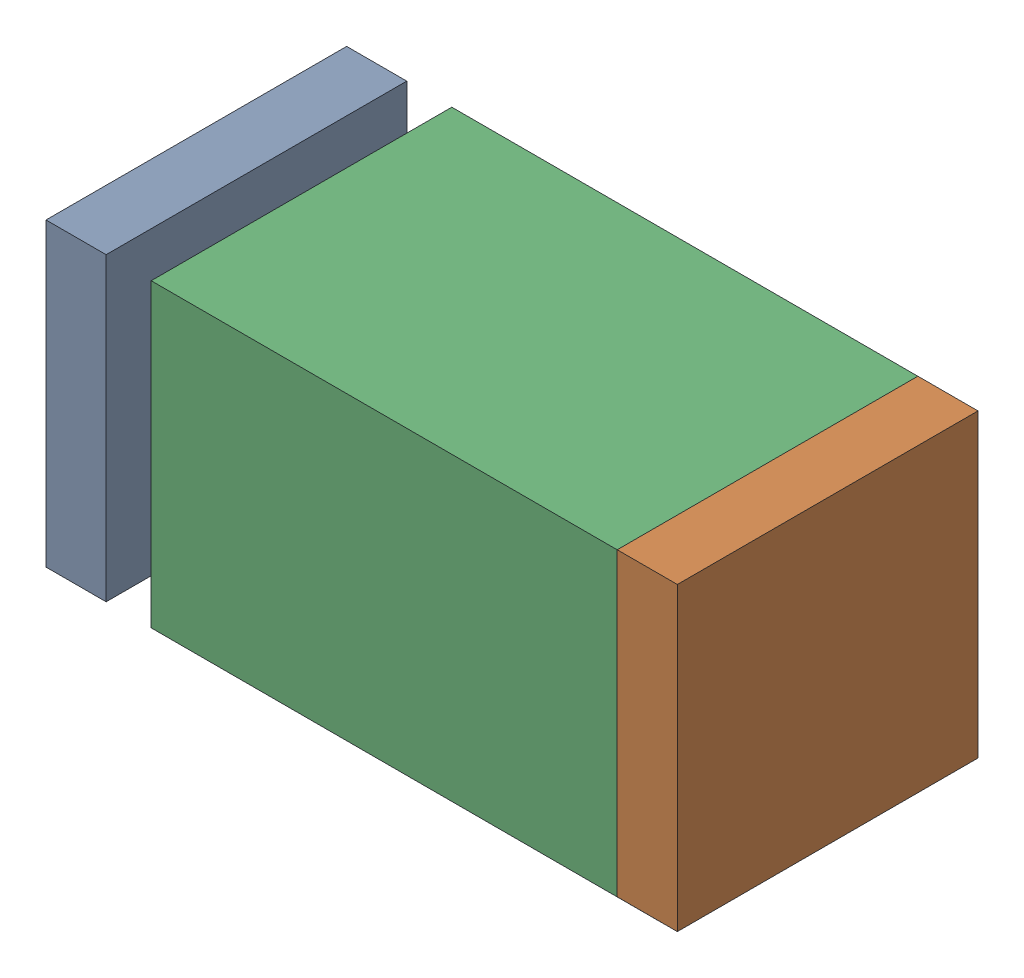
SolidWorks assembly C32, configuration Default. Lengths in mm.
Overall size (1.05 0.5 0.5).
6 component instances, 2 part files, 0 mates.
Components (placement in the parent):
- 810156080-1: 810156080 [Default] at (130.5 27.85 0) size (0.1 0.5 0.5)
  - Extruded_5-1: Extruded_5 [Default] at origin size (0.1 0.5 0.5)
- 810156080-2: 810156080 [Default] at (131.45 27.85 0) size (0.1 0.5 0.5)
  - Extruded_5-1: Extruded_5 [Default] at origin size (0.1 0.5 0.5)
- 810156208-1: 810156208 [Default] at (131.0499 27.8499 0) size (0.85 0.5 0.5)
  - Extruded_17-1: Extruded_17 [Default] at origin size (0.85 0.5 0.5)
